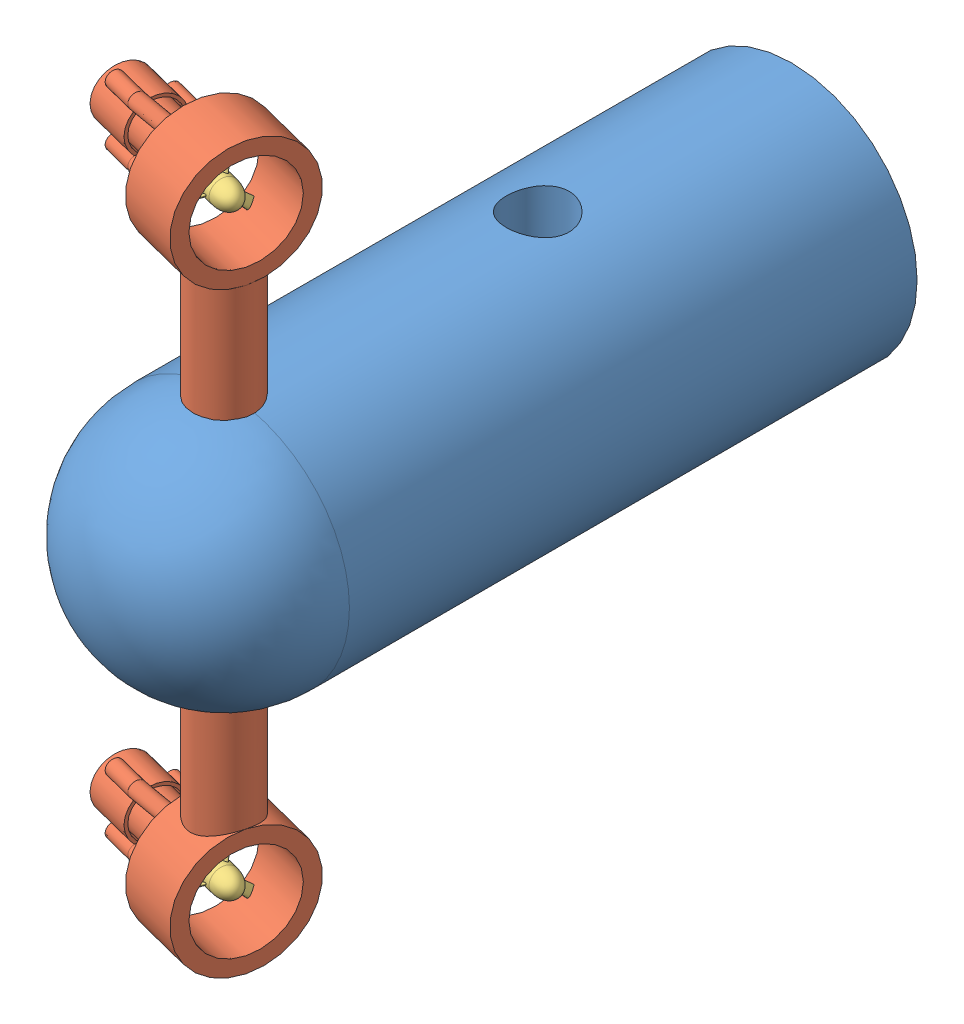
SolidWorks assembly Assem1, configuration Default. Lengths in mm.
Overall size (112.21 292.1 280.56).
4 component instances, 3 part files, 4 mates.
Components (placement in the parent):
- propulsion body 1-1: propulsion body 1 [Default] at (-45.1442 -8.7737 -110.4952) size (101.6 101.6 280.56)
- propulsion arm 1-1: propulsion arm 1 [Default] at (-45.1442 92.8263 119.2607) x (-0.96899 0 -0.2471) z (0 -1 0) size (69.34 53.98 292.1)
- propeller-1: propeller [Default] at (-37.5144 -129.4237 121.2064) x (0.061058 -0.96899 -0.239437) z (-0.239437 -0.2471 0.938942) size (32.98 15.24 28.83)
- propeller-2: propeller [Default] at (-37.5144 111.8763 121.2064) x (0.061058 -0.96899 -0.239437) z (-0.239437 -0.2471 0.938942) size (32.98 15.24 28.83)
Mates (geometry in assembly coordinates):
- Concentric1: concentric: cylinder of propulsion body 1-1 through (-45.1442 219.8263 119.2607) axis (0 -1 0) radius 12.7; cylinder of propulsion arm 1-1 through (-45.1442 -110.3737 119.2607) axis (0 1 0) radius 12.446
- Distance2: distance = 6.35 mm aligned: plane of propulsion arm 1-1 through (-45.1442 -21.4737 119.2607) normal (0 1 0); plane of propulsion body 1-1 through (-19.7442 -15.1237 19.0129) normal (0 1 0)
- Coincident3: coincident anti-aligned: circle of propulsion arm 1-1; circle of propeller-1
- Coincident7: coincident aligned: circle of propulsion arm 1-1; circle of propeller-2
